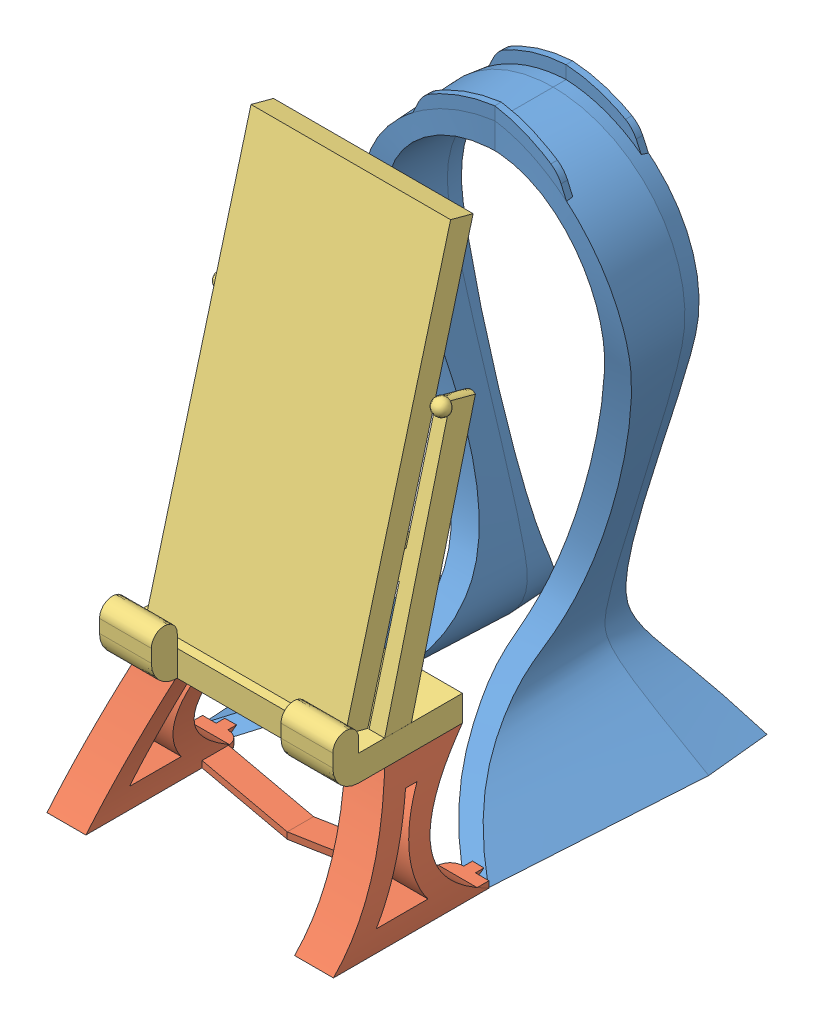
SolidWorks assembly full_assembly, configuration Domyślna. Lengths in mm.
Overall size (120 214 165.02).
4 component instances, 3 part files, 3 mates.
Components (placement in the parent):
- headphones_base-1: headphones_base [Domyślna] at (-15.498 -92.4698 205.0201) size (120 205.02 105.02)
- phone_assembly-1: phone_assembly [Domyślna] at (-8.5902 -65.7683 395.6201) x (-1 0 0) z (0 0 -1) size (111.03 213.98 95)
  - legs-1: legs [Domyślna] at (6.906 -26.7015 110.6) size (111.03 50 95)
  - Phone_stand-1: Phone_stand [Domyślna] at (6.906 23.2985 60.6) x (0 0 -1) z (1 0 0) size (60.63 163.98 90.25)
Mates (geometry in assembly coordinates):
- Coincident7: coincident anti-aligned: plane of headphones_base-1 through (-15.498 -92.4698 250.0201) normal (0 0 1); plane of phone_assembly-1/legs-1 through (-60.9962 -89.9698 250.0201) normal (0 0 -1)
- Coincident8: coincident anti-aligned: plane of headphones_base-1 through (-65.4962 -89.9698 250.0201) normal (0 -1 0); plane of phone_assembly-1/legs-1 through (-15.4962 -89.9698 285.0201) normal (0 1 0)
- Coincident9: coincident anti-aligned: plane of headphones_base-1 through (-65.4962 -92.4698 250.0201) normal (1 0 0); plane of phone_assembly-1/legs-1 through (-65.4962 -89.9698 250.0201) normal (-1 0 0)
